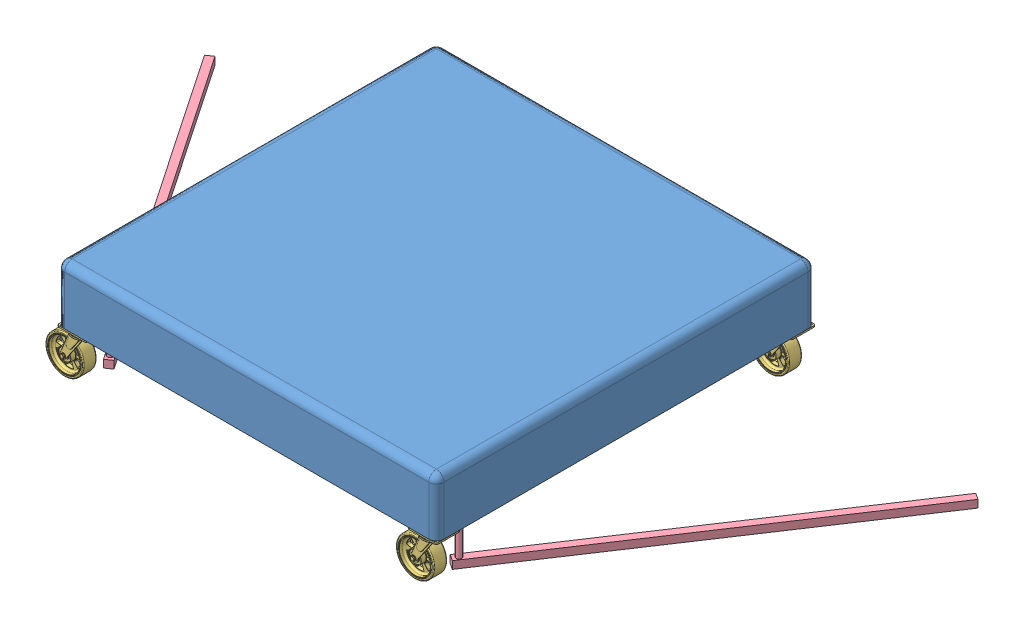
SolidWorks assembly full_coreXY_ass, configuration Default. Lengths in mm.
Overall size (2034.12 273.73 1048.26).
8 component instances, 4 part files, 18 mates.
Components (placement in the parent):
- body-1: body [Default] at (-44.1875 -65.8225 17.0821) size (1000 150 1000)
- brush-1: brush [Default] at (-44.1875 34.1775 17.0821) x (0.681029 0 -0.732256) z (-0.732256 0 -0.681029) size (741.72 210 741.72)
- swivel-1: swivel [Default] at (377.6119 -153.5116 -450.8674) size (121.23 123.73 64.1)
- swivel-2: swivel [Default] at (377.6119 -153.5116 485.0302) size (121.23 123.73 64.1)
- swivel-6: swivel [Default] at (-546.5145 -153.5116 -450.8674) size (121.23 123.73 64.1)
- swivel-7: swivel [Default] at (-546.5145 -153.5116 485.0302) size (121.23 123.73 64.1)
- wiper-1: wiper [Default] at (684.0385 -185.8225 13.0031) x (0.553043 0 -0.833153) z (0.833153 0 0.553043) size (1000 220 20)
- wiper-2: wiper [Default] at (-776.359 -185.8225 15.65) x (-0.561178 0 -0.827695) z (0.827695 0 -0.561178) size (1000 220 20)
Mates (geometry in assembly coordinates):
- Concentric1: concentric: circle of body-1; circle of brush-1
- Coincident1: coincident anti-aligned: plane of body-1 through (-44.1875 34.1775 17.0821) normal (0 -1 0); plane of brush-1 through (-44.1875 34.1775 17.0821) normal (0 1 0)
- Coincident2: coincident aligned: plane of body-1 through (-544.1875 84.1775 -482.9179) normal (0 0 -1); plane of swivel-1 through (379.9389 -65.8225 -482.9179) normal (0 0 -1)
- Coincident3: coincident anti-aligned: plane of body-1 through (-44.1875 -65.8225 17.0821) normal (0 -1 0); plane of swivel-1 through (384.586 -65.8225 -450.8667) normal (0 1 0)
- Coincident4: coincident: plane of body-1 through (455.8125 84.1775 -482.9179) normal (1 0 0); plane of swivel-1 through (455.8125 -65.8225 -418.8155) normal (1 0 0)
- Coincident5: coincident: plane of body-1 through (455.8125 84.1775 -482.9179) normal (1 0 0); plane of swivel-2 through (455.8125 -65.8225 517.0821) normal (1 0 0)
- Coincident6: coincident anti-aligned: plane of body-1 through (-44.1875 -65.8225 17.0821) normal (0 -1 0); plane of swivel-2 through (384.586 -65.8225 485.0308) normal (0 1 0)
- Coincident7: coincident aligned: plane of body-1 through (-544.1875 84.1775 517.0821) normal (0 0 1); plane of swivel-2 through (379.9389 -65.8225 517.0821) normal (0 0 1)
- Coincident14: coincident anti-aligned: plane of body-1 through (-44.1875 -65.8225 17.0821) normal (0 -1 0); plane of swivel-6 through (-539.5404 -65.8225 -450.8667) normal (0 1 0)
- Coincident15: coincident aligned: plane of body-1 through (-544.1875 84.1775 -482.9179) normal (-1 0 0); plane of swivel-6 through (-544.1875 -65.8225 -418.8155) normal (-1 0 0)
- Coincident16: coincident aligned: plane of body-1 through (-544.1875 84.1775 -482.9179) normal (0 0 -1); plane of swivel-6 through (-544.1875 -65.8225 -482.9179) normal (0 0 -1)
- Coincident17: coincident anti-aligned: plane of body-1 through (-44.1875 -65.8225 17.0821) normal (0 -1 0); plane of swivel-7 through (-539.5404 -65.8225 485.0308) normal (0 1 0)
- Coincident18: coincident aligned: plane of body-1 through (-544.1875 84.1775 -482.9179) normal (-1 0 0); plane of swivel-7 through (-544.1875 -65.8225 517.0821) normal (-1 0 0)
- Coincident19: coincident aligned: plane of body-1 through (-544.1875 84.1775 517.0821) normal (0 0 1); plane of swivel-7 through (-544.1875 -65.8225 517.0821) normal (0 0 1)
- Concentric2: concentric aligned: cylinder of body-1 through (415.8125 34.1775 417.0821) axis (0 -1 0) radius 10; cylinder of wiper-1 through (415.8125 34.1775 417.0821) axis (0 -1 0) radius 7.5
- Coincident20: coincident anti-aligned: plane of body-1 through (415.8125 34.1775 417.0821) normal (0 -1 0); plane of wiper-1 through (415.8125 34.1775 417.0821) normal (0 1 0)
- Concentric3: concentric aligned: cylinder of body-1 through (-504.1875 34.1775 417.0821) axis (0 -1 0) radius 10; cylinder of wiper-2 through (-504.1875 34.1775 417.0821) axis (0 -1 0) radius 7.5
- Coincident21: coincident anti-aligned: plane of body-1 through (-504.1875 34.1775 417.0821) normal (0 -1 0); plane of wiper-2 through (-504.1875 34.1775 417.0821) normal (0 1 0)
